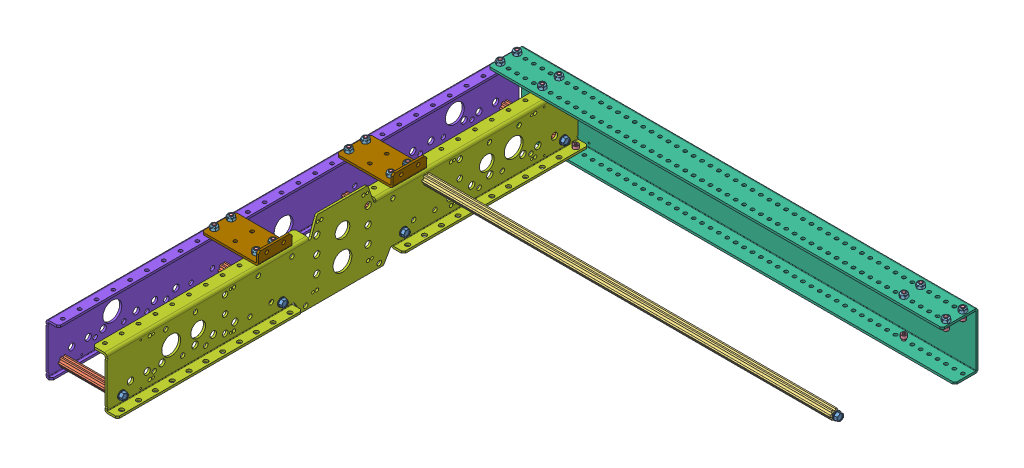
SolidWorks assembly AM14U3 Square Frame Half, configuration Default. Lengths in mm.
Overall size (722.38 428.62 726.08).
57 component instances, 10 part files, 124 mates.
Components (placement in the parent):
- 0.25-20 x 0.75 in Thread Rolling Screw-1: 0.25-20 x 0.75 in Thread Rolling Screw [FHTS 0.25-20-G-0.75-C] at (-600.075 -67.691 639.064) x (-1 0 0) z (0 0.924225 0.381849) size (24.64 12.19 12.19)
- 0.25-20 x 0.75 in Thread Rolling Screw-4: 0.25-20 x 0.75 in Thread Rolling Screw [FHTS 0.25-20-G-0.75-C] at (-600.075 -67.691 -27.94) x (-1 0 0) z (0 0.924225 0.381849) size (24.64 12.19 12.19)
- 0.25-20 x 0.75 in Thread Rolling Screw-5: 0.25-20 x 0.75 in Thread Rolling Screw [FHTS 0.25-20-G-0.75-C] at (-692.15 -67.691 -27.813) size (24.64 12.19 12.19)
- 0.25-20 x 0.75 in Thread Rolling Screw-7: 0.25-20 x 0.75 in Thread Rolling Screw [FHTS 0.25-20-G-0.75-C] at (-603.25 -15.494 178.562) size (24.64 12.19 12.19)
- 0.25-20 x 0.75 in Thread Rolling Screw-9: 0.25-20 x 0.75 in Thread Rolling Screw [FHTS 0.25-20-G-0.75-C] at (-692.15 -67.691 638.937) size (24.64 12.19 12.19)
- 0.25-20 x 0.75 in Thread Rolling Screw-10: 0.25-20 x 0.75 in Thread Rolling Screw [FHTS 0.25-20-G-0.75-C] at (19.05 -15.494 178.562) x (-1 0 0) z (0 0.525103 -0.851039) size (24.64 12.19 12.19)
- 500 Churro 3.375 in-1: 500 Churro 3.375 in [Default] at (-603.25 -67.691 -27.813) x (0 -0.866025 0.5) z (-1 0 0) size (14.66 12.7 85.72)
- 500 Churro 3.375 in-2: 500 Churro 3.375 in [Default] at (-603.25 -67.691 638.937) x (0 -0.866025 0.5) z (-1 0 0) size (14.66 12.7 85.72)
- 500 Churro 24.25 in-1: 500 Churro 24.25 in [Default] at (15.875 -15.494 178.562) x (0 0 -1) z (-1 0 0) size (14.66 12.7 615.95)
- 10-32 x 0.5 in SHCS Screw-19: 10-32 x 0.5 in SHCS Screw [HX-SHCS 0.19-32x1.375x1-C] at (-679.45 -11.43 -11.938) x (0 1 0) z (0 0 1) size (17.53 7.94 7.94)
- 10-32 x 0.5 in SHCS Screw-20: 10-32 x 0.5 in SHCS Screw [HX-SHCS 0.19-32x1.375x1-C] at (-679.45 -11.43 -37.338) x (0 1 0) z (0 0 1) size (17.53 7.94 7.94)
- 10-32 x 0.5 in SHCS Screw-21: 10-32 x 0.5 in SHCS Screw [HX-SHCS 0.19-32x1.375x1-C] at (-615.95 -11.43 -37.338) x (0 1 0) z (0 0 1) size (17.53 7.94 7.94)
- 10-32 x 0.5 in SHCS Screw-22: 10-32 x 0.5 in SHCS Screw [HX-SHCS 0.19-32x1.375x1-C] at (-615.95 -11.43 -11.938) x (0 1 0) z (0 0 1) size (17.53 7.94 7.94)
- 10-32 x 0.5 in SHCS Screw-23: 10-32 x 0.5 in SHCS Screw [HX-SHCS 0.19-32x1.375x1-C] at (-590.55 -73.152 -37.338) x (0 -1 0) z (0 0 1) size (17.53 7.94 7.94)
- 10-32 x 0.5 in SHCS Screw-24: 10-32 x 0.5 in SHCS Screw [HX-SHCS 0.19-32x1.375x1-C] at (-6.35 -11.176 -37.338) x (0 1 0) z (0.222581 0 0.974914) size (17.53 7.94 7.94)
- 10-32 x 0.5 in SHCS Screw-25: 10-32 x 0.5 in SHCS Screw [HX-SHCS 0.19-32x1.375x1-C] at (-6.35 -11.176 -11.938) x (0 1 0) z (0.81526 0 0.579096) size (17.53 7.94 7.94)
- 10-32 x 0.5 in SHCS Screw-26: 10-32 x 0.5 in SHCS Screw [HX-SHCS 0.19-32x1.375x1-C] at (-69.85 -11.176 -37.338) x (0 1 0) z (0 0 1) size (17.53 7.94 7.94)
- 10-32 x 0.5 in SHCS Screw-27: 10-32 x 0.5 in SHCS Screw [HX-SHCS 0.19-32x1.375x1-C] at (-69.85 -11.176 -11.938) x (0 1 0) z (0.111454 0 0.99377) size (17.53 7.94 7.94)
- 10-32 x 0.5 in SHCS Screw-28: 10-32 x 0.5 in SHCS Screw [HX-SHCS 0.19-32x1.375x1-C] at (-95.25 -73.406 -37.338) x (0 -1 0) z (0.007214 0 0.999974) size (17.53 7.94 7.94)
- 10-32 Nylock Nut-19: 10-32 Nylock Nut [Default] at (-679.45 0 -11.938) x (1 0 0) z (0 1 0) size (10.18 11.01 7.1)
- 10-32 Nylock Nut-21: 10-32 Nylock Nut [Default] at (-679.45 0 -37.338) x (1 0 0) z (0 1 0) size (10.18 11.01 7.1)
- 10-32 Nylock Nut-22: 10-32 Nylock Nut [Default] at (-615.95 0 -11.938) x (1 0 0) z (0 1 0) size (10.18 11.01 7.1)
- 10-32 Nylock Nut-23: 10-32 Nylock Nut [Default] at (-615.95 0 -37.338) x (1 0 0) z (0 1 0) size (10.18 11.01 7.1)
- 10-32 Nylock Nut-25: 10-32 Nylock Nut [Default] at (-69.85 0 -11.938) x (1 0 0) z (0 1 0) size (10.18 11.01 7.1)
- 10-32 Nylock Nut-26: 10-32 Nylock Nut [Default] at (-69.85 0 -37.338) x (1 0 0) z (0 1 0) size (10.18 11.01 7.1)
- 10-32 Nylock Nut-27: 10-32 Nylock Nut [Default] at (-6.35 0 -11.938) x (1 0 0) z (0 1 0) size (10.18 11.01 7.1)
- 10-32 Nylock Nut-28: 10-32 Nylock Nut [Default] at (-6.35 0 -37.338) x (1 0 0) z (0 1 0) size (10.18 11.01 7.1)
- 10-32 Nylock Nut-29: 10-32 Nylock Nut [Default] at (-95.25 -84.582 -37.338) x (1 0 0) z (0 -1 0) size (10.18 11.01 7.1)
- 10-32 Nylock Nut-30: 10-32 Nylock Nut [Default] at (-590.55 -84.582 -37.338) x (1 0 0) z (0 -1 0) size (10.18 11.01 7.1)
- 10-32 x 0.5 in SHCS Screw-29: 10-32 x 0.5 in SHCS Screw [HX-SHCS 0.19-32x1.375x1-C] at (-679.45 -11.43 191.262) x (0 1 0) z (0 0 1) size (17.53 7.94 7.94)
- 10-32 x 0.5 in SHCS Screw-30: 10-32 x 0.5 in SHCS Screw [HX-SHCS 0.19-32x1.375x1-C] at (-679.45 -11.43 216.662) x (0 1 0) z (0 0 1) size (17.53 7.94 7.94)
- 10-32 x 0.5 in SHCS Screw-31: 10-32 x 0.5 in SHCS Screw [HX-SHCS 0.19-32x1.375x1-C] at (-615.95 -11.43 191.262) x (0 1 0) z (0 0 1) size (17.53 7.94 7.94)
- 10-32 x 0.5 in SHCS Screw-32: 10-32 x 0.5 in SHCS Screw [HX-SHCS 0.19-32x1.375x1-C] at (-615.95 -11.43 216.662) x (0 1 0) z (0 0 1) size (17.53 7.94 7.94)
- 10-32 x 0.5 in SHCS Screw-33: 10-32 x 0.5 in SHCS Screw [HX-SHCS 0.19-32x1.375x1-C] at (-615.95 -11.43 394.462) x (0 1 0) z (0 0 1) size (17.53 7.94 7.94)
- 10-32 x 0.5 in SHCS Screw-34: 10-32 x 0.5 in SHCS Screw [HX-SHCS 0.19-32x1.375x1-C] at (-615.95 -11.43 419.862) x (0 1 0) z (0 0 1) size (17.53 7.94 7.94)
- 10-32 x 0.5 in SHCS Screw-35: 10-32 x 0.5 in SHCS Screw [HX-SHCS 0.19-32x1.375x1-C] at (-679.45 -11.43 394.462) x (0 1 0) z (0 0 1) size (17.53 7.94 7.94)
- 10-32 x 0.5 in SHCS Screw-36: 10-32 x 0.5 in SHCS Screw [HX-SHCS 0.19-32x1.375x1-C] at (-679.45 -11.43 419.862) x (0 1 0) z (0 0 1) size (17.53 7.94 7.94)
- 10-32 Nylock Nut-31: 10-32 Nylock Nut [Default] at (-679.45 -0.254 419.862) x (1 0 0) z (0 1 0) size (10.18 11.01 7.1)
- 10-32 Nylock Nut-32: 10-32 Nylock Nut [Default] at (-679.45 -0.254 394.462) x (1 0 0) z (0 1 0) size (10.18 11.01 7.1)
- 10-32 Nylock Nut-33: 10-32 Nylock Nut [Default] at (-615.95 -0.254 394.462) x (1 0 0) z (0 1 0) size (10.18 11.01 7.1)
- 10-32 Nylock Nut-34: 10-32 Nylock Nut [Default] at (-615.95 -0.254 419.862) x (1 0 0) z (0 1 0) size (10.18 11.01 7.1)
- 10-32 Nylock Nut-35: 10-32 Nylock Nut [Default] at (-679.45 -0.254 216.662) x (1 0 0) z (0 1 0) size (10.18 11.01 7.1)
- 10-32 Nylock Nut-37: 10-32 Nylock Nut [Default] at (-679.45 -0.254 191.262) x (1 0 0) z (0 1 0) size (10.18 11.01 7.1)
- 10-32 Nylock Nut-38: 10-32 Nylock Nut [Default] at (-615.95 -0.254 216.662) x (1 0 0) z (0 1 0) size (10.18 11.01 7.1)
- 10-32 Nylock Nut-39: 10-32 Nylock Nut [Default] at (-615.95 -0.254 191.262) x (1 0 0) z (0 1 0) size (10.18 11.01 7.1)
- AM14U3 End Plate_Square-1: AM14U3 End Plate_Square [Default] at (-488.098 60.9785 -76.8664) x (1 0 0) z (0 -1 0) size (685.8 53.97 84.58)
- AM14U3 Inner Plate_Square-1: AM14U3 Inner Plate_Square [Default] at (-612.1116 -19.2169 590.6409) x (0 0 -1) z (0 -1 0) size (711.2 38.1 116.33)
- AM14U3 Outer Plate_Square-1: AM14U3 Outer Plate_Square [Default] at (-667.7485 -27.0221 21.6115) x (0 0 1) z (0 -1 0) size (711.2 19.05 77.72)
- Bracket 2x3 Hole Pattern-1: Bracket 2x3 Hole Pattern [Default] at (-685.8 -3.429 445.262) size (85.72 19.05 50.8)
- Bracket 2x3 Hole Pattern-2: Bracket 2x3 Hole Pattern [Default] at (-685.8 -3.429 242.062) size (85.72 19.05 50.8)
- 500 Churro 3.375 in-5: 500 Churro 3.375 in [Default] at (-688.975 -66.929 397.637) x (0 0 -1) z (1 0 0) size (14.66 12.7 85.72)
- 500 Churro 3.375 in-6: 500 Churro 3.375 in [Default] at (-688.975 -66.929 213.487) x (0 0 -1) z (1 0 0) size (14.66 12.7 85.72)
- 0.25-20 x 0.75 in Thread Rolling Screw-11: 0.25-20 x 0.75 in Thread Rolling Screw [FHTS 0.25-20-G-0.75-C] at (-600.075 -66.929 397.637) x (-1 0 0) z (0 0.924225 0.381849) size (24.64 12.19 12.19)
- 0.25-20 x 0.75 in Thread Rolling Screw-12: 0.25-20 x 0.75 in Thread Rolling Screw [FHTS 0.25-20-G-0.75-C] at (-600.075 -66.929 213.487) x (-1 0 0) z (0 0.924225 0.381849) size (24.64 12.19 12.19)
- 0.25-20 x 0.75 in Thread Rolling Screw-13: 0.25-20 x 0.75 in Thread Rolling Screw [FHTS 0.25-20-G-0.75-C] at (-692.15 -66.929 397.637) size (24.64 12.19 12.19)
- 0.25-20 x 0.75 in Thread Rolling Screw-14: 0.25-20 x 0.75 in Thread Rolling Screw [FHTS 0.25-20-G-0.75-C] at (-692.15 -66.929 213.487) size (24.64 12.19 12.19)
- side-view-with-wheels-1: side-view-with-wheels [Default] x (0 0 -1) z (1 0 0) size (718.98 241.48 0)
Mates (geometry in assembly coordinates):
- Coincident1: coincident aligned: plane of AM14U3 End Plate_Square-1 through (0 0 0) normal (0 1 0); plane of assembly through (0 0 0) normal (0 1 0)
- Coincident2: coincident aligned: plane of AM14U3 End Plate_Square-1 through (0 0 0) normal (0 0 1); plane of assembly through (0 0 0) normal (0 0 1)
- Coincident3: coincident aligned: plane of AM14U3 End Plate_Square-1 through (0 -81.407 -50.8) normal (1 0 0); plane of assembly through (0 0 0) normal (1 0 0)
- Concentric1: concentric anti-aligned: cylinder of AM14U3 End Plate_Square-1 through (-679.45 0 -37.338) axis (0 -1 0) radius 2.667; cylinder of AM14U3 Outer Plate_Square-1 through (-679.45 -81.153 -37.338) axis (0 1 0) radius 2.667
- Concentric2: concentric aligned: cylinder of AM14U3 End Plate_Square-1 through (-679.45 -5.08 -11.938) axis (0 1 0) radius 2.667; cylinder of AM14U3 Outer Plate_Square-1 through (-679.45 -81.153 -11.938) axis (0 1 0) radius 2.667
- Concentric3: concentric anti-aligned: cylinder of AM14U3 End Plate_Square-1 through (-615.95 0 -37.338) axis (0 -1 0) radius 2.667; cylinder of AM14U3 Inner Plate_Square-1 through (-615.95 -81.153 -37.338) axis (0 1 0) radius 2.667
- Coincident5: coincident aligned: circle of AM14U3 End Plate_Square-1; cylinder of AM14U3 Inner Plate_Square-1 through (-615.95 -81.153 -11.938) axis (0 1 0) radius 2.667
- Distance2: distance = 0.254 mm anti-aligned: plane of AM14U3 Inner Plate_Square-1 through (-603.25 -3.429 -100.838) normal (0 1 0); plane of AM14U3 End Plate_Square-1 through (0 -3.175 0) normal (0 -1 0)
- Concentric4: concentric aligned: cylinder of AM14U3 Inner Plate_Square-1 through (-615.95 -81.153 394.462) axis (0 1 0) radius 2.667; cylinder of Bracket 2x3 Hole Pattern-1 through (-615.95 -3.429 394.462) axis (0 1 0) radius 2.667
- Coincident7: coincident aligned: cylinder of AM14U3 Inner Plate_Square-1 through (-615.95 -81.153 419.862) axis (0 1 0) radius 2.667; circle of Bracket 2x3 Hole Pattern-1
- Coincident8: coincident anti-aligned: plane of AM14U3 Inner Plate_Square-1 through (-603.25 -3.429 -100.838) normal (0 1 0); plane of Bracket 2x3 Hole Pattern-1 through (-685.8 -3.429 381.762) normal (0 -1 0)
- Concentric5: concentric aligned: cylinder of AM14U3 Inner Plate_Square-1 through (-615.95 -81.153 216.662) axis (0 1 0) radius 2.667; cylinder of Bracket 2x3 Hole Pattern-2 through (-615.95 -3.429 216.662) axis (0 1 0) radius 2.667
- Concentric6: concentric aligned: cylinder of AM14U3 Inner Plate_Square-1 through (-615.95 -81.153 191.262) axis (0 1 0) radius 2.667; cylinder of Bracket 2x3 Hole Pattern-2 through (-615.95 -3.429 191.262) axis (0 1 0) radius 2.667
- Coincident9: coincident anti-aligned: plane of AM14U3 Inner Plate_Square-1 through (-603.25 -3.429 -100.838) normal (0 1 0); plane of Bracket 2x3 Hole Pattern-2 through (-685.8 -3.429 178.562) normal (0 -1 0)
- Concentric25: concentric anti-aligned: cylinder of AM14U3 Outer Plate_Square-1 through (-673.1 -67.691 -27.813) axis (-1 0 0) radius 3.3528; cylinder of 500 Churro 3.375 in-1 through (-688.975 -67.691 -27.813) axis (1 0 0) radius 2.9337
- Concentric26: concentric anti-aligned: cylinder of AM14U3 Outer Plate_Square-1 through (-673.1 -67.691 638.937) axis (-1 0 0) radius 3.3528; cylinder of 500 Churro 3.375 in-2 through (-688.975 -67.691 638.937) axis (1 0 0) radius 2.9337
- Coincident28: coincident anti-aligned: plane of AM14U3 Outer Plate_Square-1 through (-688.975 -7.366 -100.838) normal (1 0 0); plane of 500 Churro 3.375 in-2 through (-688.975 -70.866 644.4363) normal (-1 0 0)
- Parallel1: parallel aligned: plane of AM14U3 Outer Plate_Square-1 through (-688.975 -81.153 711.962) normal (0 -1 0); plane of 500 Churro 3.375 in-2 through (-688.975 -74.041 635.2708) normal (0 -1 0)
- Coincident30: coincident anti-aligned: plane of AM14U3 Outer Plate_Square-1 through (-688.975 -7.366 -100.838) normal (1 0 0); plane of 500 Churro 3.375 in-1 through (-688.975 -70.866 -22.3137) normal (-1 0 0)
- Parallel2: parallel aligned: plane of AM14U3 Outer Plate_Square-1 through (-688.975 -81.153 711.962) normal (0 -1 0); plane of 500 Churro 3.375 in-1 through (-688.975 -74.041 -31.4792) normal (0 -1 0)
- Distance3: distance = 0.254 mm anti-aligned: plane of AM14U3 Outer Plate_Square-1 through (-688.975 -3.429 711.962) normal (0 1 0); plane of AM14U3 End Plate_Square-1 through (0 -3.175 0) normal (0 -1 0)
- Concentric29: concentric anti-aligned: circle of AM14U3 Inner Plate_Square-1; cylinder of 500 Churro 24.25 in-1 through (-600.075 -15.494 178.562) axis (1 0 0) radius 2.9337
- Coincident37: coincident anti-aligned: plane of AM14U3 Inner Plate_Square-1 through (-600.075 -7.366 711.962) normal (1 0 0); plane of 500 Churro 24.25 in-1 through (-600.075 -18.669 173.0627) normal (-1 0 0)
- Concentric301: concentric aligned: cylinder of AM14U3 Inner Plate_Square-1 through (-622.3 -67.691 639.064) axis (1 0 0) radius 3.3528; cylinder of 0.25-20 x 0.75 in Thread Rolling Screw-1 through (-600.075 -67.691 639.064) axis (1 0 0) radius 3.175
- Coincident381: coincident anti-aligned: plane of AM14U3 Inner Plate_Square-1 through (-600.075 -7.366 711.962) normal (1 0 0); plane of 0.25-20 x 0.75 in Thread Rolling Screw-1 through (-600.075 -68.9034 641.9984) normal (-1 0 0)
- Concentric331: concentric aligned: cylinder of AM14U3 Inner Plate_Square-1 through (-622.3 -67.691 -27.94) axis (1 0 0) radius 3.3528; cylinder of 0.25-20 x 0.75 in Thread Rolling Screw-4 through (-600.075 -67.691 -27.94) axis (1 0 0) radius 3.175
- Coincident411: coincident anti-aligned: plane of AM14U3 Inner Plate_Square-1 through (-600.075 -7.366 711.962) normal (1 0 0); plane of 0.25-20 x 0.75 in Thread Rolling Screw-4 through (-600.075 -68.9034 -25.0056) normal (-1 0 0)
- Concentric341: concentric aligned: cylinder of AM14U3 Outer Plate_Square-1 through (-673.1 -67.691 -27.813) axis (-1 0 0) radius 3.3528; cylinder of 0.25-20 x 0.75 in Thread Rolling Screw-5 through (-692.15 -67.691 -27.813) axis (-1 0 0) radius 3.175
- Coincident421: coincident anti-aligned: plane of AM14U3 Outer Plate_Square-1 through (-692.15 -7.366 -100.838) normal (-1 0 0); plane of 0.25-20 x 0.75 in Thread Rolling Screw-5 through (-692.15 -64.516 -27.813) normal (1 0 0)
- Concentric361: concentric aligned: cylinder of AM14U3 Inner Plate_Square-1 through (-584.2 -15.494 178.562) axis (-1 0 0) radius 3.3528; cylinder of 0.25-20 x 0.75 in Thread Rolling Screw-7 through (-603.25 -15.494 178.562) axis (-1 0 0) radius 3.175
- Coincident441: coincident anti-aligned: plane of AM14U3 Inner Plate_Square-1 through (-603.25 -7.366 711.962) normal (-1 0 0); plane of 0.25-20 x 0.75 in Thread Rolling Screw-7 through (-603.25 -12.319 178.562) normal (1 0 0)
- Concentric381: concentric aligned: cylinder of AM14U3 Outer Plate_Square-1 through (-673.1 -67.691 638.937) axis (-1 0 0) radius 3.3528; cylinder of 0.25-20 x 0.75 in Thread Rolling Screw-9 through (-692.15 -67.691 638.937) axis (-1 0 0) radius 3.175
- Coincident461: coincident anti-aligned: plane of AM14U3 Outer Plate_Square-1 through (-692.15 -7.366 -100.838) normal (-1 0 0); plane of 0.25-20 x 0.75 in Thread Rolling Screw-9 through (-692.15 -64.516 638.937) normal (1 0 0)
- Concentric39: concentric aligned: cylinder of 500 Churro 24.25 in-1 through (-600.075 -15.494 178.562) axis (1 0 0) radius 2.9337; cylinder of 0.25-20 x 0.75 in Thread Rolling Screw-10 through (19.05 -15.494 178.562) axis (1 0 0) radius 3.175
- Distance4: distance = 3.175 mm anti-aligned: plane of 500 Churro 24.25 in-1 through (15.875 -18.669 173.0627) normal (1 0 0); plane of 0.25-20 x 0.75 in Thread Rolling Screw-10 through (19.05 -12.792 180.2292) normal (-1 0 0)
- Parallel5: parallel aligned: plane of AM14U3 Inner Plate_Square-1 through (-603.25 -3.429 -100.838) normal (0 1 0); plane of 500 Churro 24.25 in-1 through (-600.075 -9.144 176.9745) normal (0 1 0)
- Concentric4721: concentric anti-aligned: cylinder of AM14U3 Outer Plate_Square-1 through (-679.45 -81.153 -11.938) axis (0 1 0) radius 2.667; cylinder of 10-32 x 0.5 in SHCS Screw-19 through (-679.45 -43.18 -11.938) axis (0 -1 0) radius 3.9688
- Coincident5621: coincident anti-aligned: plane of AM14U3 Outer Plate_Square-1 through (-688.975 -6.604 711.962) normal (0 -1 0); plane of 10-32 x 0.5 in SHCS Screw-19 through (-683.4187 -6.604 -11.938) normal (0 1 0)
- Concentric4731: concentric anti-aligned: cylinder of AM14U3 Outer Plate_Square-1 through (-679.45 -81.153 -37.338) axis (0 1 0) radius 2.667; cylinder of 10-32 x 0.5 in SHCS Screw-20 through (-679.45 -43.18 -37.338) axis (0 -1 0) radius 3.9688
- Coincident5631: coincident anti-aligned: plane of AM14U3 Outer Plate_Square-1 through (-688.975 -6.604 711.962) normal (0 -1 0); plane of 10-32 x 0.5 in SHCS Screw-20 through (-683.4187 -6.604 -37.338) normal (0 1 0)
- Concentric4741: concentric anti-aligned: cylinder of AM14U3 Inner Plate_Square-1 through (-615.95 -81.153 -37.338) axis (0 1 0) radius 2.667; cylinder of 10-32 x 0.5 in SHCS Screw-21 through (-615.95 -43.18 -37.338) axis (0 -1 0) radius 3.9688
- Coincident5641: coincident anti-aligned: plane of AM14U3 Inner Plate_Square-1 through (-603.25 -6.604 -100.838) normal (0 -1 0); plane of 10-32 x 0.5 in SHCS Screw-21 through (-619.9187 -6.604 -37.338) normal (0 1 0)
- Concentric4751: concentric anti-aligned: cylinder of AM14U3 Inner Plate_Square-1 through (-615.95 -81.153 -11.938) axis (0 1 0) radius 2.667; cylinder of 10-32 x 0.5 in SHCS Screw-22 through (-615.95 -43.18 -11.938) axis (0 -1 0) radius 3.9688
- Coincident5651: coincident anti-aligned: plane of AM14U3 Inner Plate_Square-1 through (-603.25 -6.604 -100.838) normal (0 -1 0); plane of 10-32 x 0.5 in SHCS Screw-22 through (-619.9187 -6.604 -11.938) normal (0 1 0)
- Concentric4761: concentric aligned: cylinder of AM14U3 Inner Plate_Square-1 through (-590.55 -81.153 -37.338) axis (0 1 0) radius 3.3528; cylinder of 10-32 x 0.5 in SHCS Screw-23 through (-590.55 -41.402 -37.338) axis (0 1 0) radius 3.9688
- Coincident5661: coincident anti-aligned: plane of AM14U3 Inner Plate_Square-1 through (-600.075 -77.978 -100.838) normal (0 1 0); plane of 10-32 x 0.5 in SHCS Screw-23 through (-586.5813 -77.978 -37.338) normal (0 -1 0)
- Concentric478: concentric aligned: cylinder of AM14U3 End Plate_Square-1 through (-6.35 0 -37.338) axis (0 -1 0) radius 2.667; cylinder of 10-32 x 0.5 in SHCS Screw-24 through (-6.35 -42.926 -37.338) axis (0 -1 0) radius 2.413
- Concentric479: concentric anti-aligned: cylinder of AM14U3 End Plate_Square-1 through (-6.35 -5.08 -11.938) axis (0 1 0) radius 2.667; cylinder of 10-32 x 0.5 in SHCS Screw-25 through (-6.35 -42.926 -11.938) axis (0 -1 0) radius 2.413
- Coincident567: coincident aligned: plane of 10-32 x 0.5 in SHCS Screw-24 through (-10.2192 -6.35 -36.4546) normal (0 1 0); plane of 10-32 x 0.5 in SHCS Screw-25 through (-8.6483 -6.35 -8.7024) normal (0 1 0)
- Concentric480: concentric aligned: cylinder of AM14U3 End Plate_Square-1 through (-69.85 0 -37.338) axis (0 -1 0) radius 2.667; cylinder of 10-32 x 0.5 in SHCS Screw-26 through (-69.85 -42.926 -37.338) axis (0 -1 0) radius 2.413
- Concentric481: concentric anti-aligned: cylinder of AM14U3 End Plate_Square-1 through (-69.85 -5.08 -11.938) axis (0 1 0) radius 2.667; cylinder of 10-32 x 0.5 in SHCS Screw-27 through (-69.85 -42.926 -11.938) axis (0 -1 0) radius 2.413
- Coincident568: coincident aligned: plane of 10-32 x 0.5 in SHCS Screw-26 through (-73.8188 -6.35 -37.338) normal (0 1 0); plane of 10-32 x 0.5 in SHCS Screw-27 through (-73.794 -6.35 -11.4957) normal (0 1 0)
- Coincident569: coincident aligned: plane of 10-32 x 0.5 in SHCS Screw-25 through (-8.6483 -6.35 -8.7024) normal (0 1 0); plane of 10-32 x 0.5 in SHCS Screw-27 through (-73.794 -6.35 -11.4957) normal (0 1 0)
- Distance5: distance = 3.175 mm anti-aligned: plane of AM14U3 End Plate_Square-1 through (0 -3.175 0) normal (0 -1 0); plane of 10-32 x 0.5 in SHCS Screw-27 through (-73.794 -6.35 -11.4957) normal (0 1 0)
- Concentric482: concentric aligned: circle of AM14U3 End Plate_Square-1; cylinder of 10-32 x 0.5 in SHCS Screw-28 through (-95.25 -41.656 -37.338) axis (0 1 0) radius 2.413
- Distance6: distance = 3.175 mm anti-aligned: plane of AM14U3 End Plate_Square-1 through (-787.4 -81.407 -19.05) normal (0 1 0); plane of 10-32 x 0.5 in SHCS Screw-28 through (-91.2814 -78.232 -37.3666) normal (0 -1 0)
- Concentric4831: concentric aligned: cylinder of AM14U3 End Plate_Square-1 through (-679.45 -5.08 -11.938) axis (0 1 0) radius 2.667; cylinder of 10-32 Nylock Nut-19 through (-679.45 5.9531 -11.938) axis (0 1 0) radius 2.0193
- Coincident5721: coincident anti-aligned: plane of AM14U3 End Plate_Square-1 through (0 0 0) normal (0 1 0); plane of 10-32 Nylock Nut-19 through (-679.45 0 -11.938) normal (0 -1 0)
- Concentric4841: concentric anti-aligned: cylinder of AM14U3 End Plate_Square-1 through (-679.45 0 -37.338) axis (0 -1 0) radius 2.667; cylinder of 10-32 Nylock Nut-21 through (-679.45 5.9531 -37.338) axis (0 1 0) radius 2.0193
- Coincident5731: coincident anti-aligned: plane of AM14U3 End Plate_Square-1 through (0 0 0) normal (0 1 0); plane of 10-32 Nylock Nut-21 through (-679.45 0 -37.338) normal (0 -1 0)
- Concentric4851: concentric aligned: cylinder of AM14U3 End Plate_Square-1 through (-615.95 -5.08 -11.938) axis (0 1 0) radius 2.667; cylinder of 10-32 Nylock Nut-22 through (-615.95 5.9531 -11.938) axis (0 1 0) radius 2.0193
- Coincident5741: coincident anti-aligned: plane of AM14U3 End Plate_Square-1 through (0 0 0) normal (0 1 0); plane of 10-32 Nylock Nut-22 through (-615.95 0 -11.938) normal (0 -1 0)
- Concentric4861: concentric anti-aligned: cylinder of AM14U3 End Plate_Square-1 through (-615.95 0 -37.338) axis (0 -1 0) radius 2.667; cylinder of 10-32 Nylock Nut-23 through (-615.95 5.9531 -37.338) axis (0 1 0) radius 2.0193
- Coincident5751: coincident anti-aligned: plane of AM14U3 End Plate_Square-1 through (0 0 0) normal (0 1 0); plane of 10-32 Nylock Nut-23 through (-615.95 0 -37.338) normal (0 -1 0)
- Concentric4871: concentric aligned: cylinder of AM14U3 End Plate_Square-1 through (-69.85 -5.08 -11.938) axis (0 1 0) radius 2.667; cylinder of 10-32 Nylock Nut-25 through (-69.85 5.9531 -11.938) axis (0 1 0) radius 2.0193
- Coincident5771: coincident anti-aligned: plane of AM14U3 End Plate_Square-1 through (0 0 0) normal (0 1 0); plane of 10-32 Nylock Nut-25 through (-69.85 0 -11.938) normal (0 -1 0)
- Concentric4881: concentric anti-aligned: cylinder of AM14U3 End Plate_Square-1 through (-69.85 0 -37.338) axis (0 -1 0) radius 2.667; cylinder of 10-32 Nylock Nut-26 through (-69.85 5.9531 -37.338) axis (0 1 0) radius 2.0193
- Coincident5781: coincident anti-aligned: plane of AM14U3 End Plate_Square-1 through (0 0 0) normal (0 1 0); plane of 10-32 Nylock Nut-26 through (-69.85 0 -37.338) normal (0 -1 0)
- Concentric4891: concentric aligned: cylinder of AM14U3 End Plate_Square-1 through (-6.35 -5.08 -11.938) axis (0 1 0) radius 2.667; cylinder of 10-32 Nylock Nut-27 through (-6.35 5.9531 -11.938) axis (0 1 0) radius 2.0193
- Coincident5791: coincident anti-aligned: plane of AM14U3 End Plate_Square-1 through (0 0 0) normal (0 1 0); plane of 10-32 Nylock Nut-27 through (-6.35 0 -11.938) normal (0 -1 0)
- Concentric4901: concentric anti-aligned: cylinder of AM14U3 End Plate_Square-1 through (-6.35 0 -37.338) axis (0 -1 0) radius 2.667; cylinder of 10-32 Nylock Nut-28 through (-6.35 5.9531 -37.338) axis (0 1 0) radius 2.0193
- Coincident5801: coincident anti-aligned: plane of AM14U3 End Plate_Square-1 through (0 0 0) normal (0 1 0); plane of 10-32 Nylock Nut-28 through (-6.35 0 -37.338) normal (0 -1 0)
- Concentric4911: concentric aligned: cylinder of AM14U3 End Plate_Square-1 through (-95.25 0 -37.338) axis (0 -1 0) radius 2.667; cylinder of 10-32 Nylock Nut-29 through (-95.25 -90.5351 -37.338) axis (0 -1 0) radius 2.0193
- Coincident5811: coincident anti-aligned: plane of AM14U3 End Plate_Square-1 through (-787.4 -84.582 -19.05) normal (0 -1 0); plane of 10-32 Nylock Nut-29 through (-95.25 -84.582 -37.338) normal (0 1 0)
- Concentric4921: concentric aligned: cylinder of AM14U3 End Plate_Square-1 through (-590.55 0 -37.338) axis (0 -1 0) radius 2.667; cylinder of 10-32 Nylock Nut-30 through (-590.55 -90.5351 -37.338) axis (0 -1 0) radius 2.0193
- Coincident5821: coincident anti-aligned: plane of AM14U3 End Plate_Square-1 through (-787.4 -84.582 -19.05) normal (0 -1 0); plane of 10-32 Nylock Nut-30 through (-590.55 -84.582 -37.338) normal (0 1 0)
- Concentric4931: concentric anti-aligned: cylinder of AM14U3 Outer Plate_Square-1 through (-679.45 -81.153 191.262) axis (0 1 0) radius 2.667; cylinder of 10-32 x 0.5 in SHCS Screw-29 through (-679.45 -43.18 191.262) axis (0 -1 0) radius 3.9688
- Coincident5831: coincident anti-aligned: plane of AM14U3 Outer Plate_Square-1 through (-688.975 -6.604 711.962) normal (0 -1 0); plane of 10-32 x 0.5 in SHCS Screw-29 through (-683.4187 -6.604 191.262) normal (0 1 0)
- Concentric4941: concentric anti-aligned: cylinder of AM14U3 Outer Plate_Square-1 through (-679.45 -81.153 216.662) axis (0 1 0) radius 2.667; cylinder of 10-32 x 0.5 in SHCS Screw-30 through (-679.45 -43.18 216.662) axis (0 -1 0) radius 3.9688
- Coincident5841: coincident anti-aligned: plane of AM14U3 Outer Plate_Square-1 through (-688.975 -6.604 711.962) normal (0 -1 0); plane of 10-32 x 0.5 in SHCS Screw-30 through (-683.4187 -6.604 216.662) normal (0 1 0)
- Concentric4951: concentric anti-aligned: cylinder of AM14U3 Inner Plate_Square-1 through (-615.95 -81.153 191.262) axis (0 1 0) radius 2.667; cylinder of 10-32 x 0.5 in SHCS Screw-31 through (-615.95 -43.18 191.262) axis (0 -1 0) radius 3.9688
- Coincident5851: coincident anti-aligned: plane of AM14U3 Inner Plate_Square-1 through (-603.25 -6.604 -100.838) normal (0 -1 0); plane of 10-32 x 0.5 in SHCS Screw-31 through (-619.9187 -6.604 191.262) normal (0 1 0)
- Concentric4961: concentric anti-aligned: cylinder of AM14U3 Inner Plate_Square-1 through (-615.95 -81.153 216.662) axis (0 1 0) radius 2.667; cylinder of 10-32 x 0.5 in SHCS Screw-32 through (-615.95 -43.18 216.662) axis (0 -1 0) radius 3.9688
- Coincident5861: coincident anti-aligned: plane of AM14U3 Inner Plate_Square-1 through (-603.25 -6.604 -100.838) normal (0 -1 0); plane of 10-32 x 0.5 in SHCS Screw-32 through (-619.9187 -6.604 216.662) normal (0 1 0)
- Concentric4971: concentric anti-aligned: cylinder of AM14U3 Inner Plate_Square-1 through (-615.95 -81.153 394.462) axis (0 1 0) radius 2.667; cylinder of 10-32 x 0.5 in SHCS Screw-33 through (-615.95 -43.18 394.462) axis (0 -1 0) radius 3.9688
- Coincident5871: coincident anti-aligned: plane of AM14U3 Inner Plate_Square-1 through (-603.25 -6.604 -100.838) normal (0 -1 0); plane of 10-32 x 0.5 in SHCS Screw-33 through (-619.9187 -6.604 394.462) normal (0 1 0)
- Concentric4981: concentric anti-aligned: cylinder of AM14U3 Inner Plate_Square-1 through (-615.95 -81.153 419.862) axis (0 1 0) radius 2.667; cylinder of 10-32 x 0.5 in SHCS Screw-34 through (-615.95 -43.18 419.862) axis (0 -1 0) radius 3.9688
- Coincident5881: coincident anti-aligned: plane of AM14U3 Inner Plate_Square-1 through (-603.25 -6.604 -100.838) normal (0 -1 0); plane of 10-32 x 0.5 in SHCS Screw-34 through (-619.9187 -6.604 419.862) normal (0 1 0)
- Concentric4991: concentric anti-aligned: cylinder of AM14U3 Outer Plate_Square-1 through (-679.45 -81.153 394.462) axis (0 1 0) radius 2.667; cylinder of 10-32 x 0.5 in SHCS Screw-35 through (-679.45 -43.18 394.462) axis (0 -1 0) radius 3.9688
- Coincident5891: coincident anti-aligned: plane of AM14U3 Outer Plate_Square-1 through (-688.975 -6.604 711.962) normal (0 -1 0); plane of 10-32 x 0.5 in SHCS Screw-35 through (-683.4187 -6.604 394.462) normal (0 1 0)
- Concentric5001: concentric anti-aligned: cylinder of AM14U3 Outer Plate_Square-1 through (-679.45 -81.153 419.862) axis (0 1 0) radius 2.667; cylinder of 10-32 x 0.5 in SHCS Screw-36 through (-679.45 -43.18 419.862) axis (0 -1 0) radius 3.9688
- Coincident5901: coincident anti-aligned: plane of AM14U3 Outer Plate_Square-1 through (-688.975 -6.604 711.962) normal (0 -1 0); plane of 10-32 x 0.5 in SHCS Screw-36 through (-683.4187 -6.604 419.862) normal (0 1 0)
- Concentric5011: concentric aligned: cylinder of Bracket 2x3 Hole Pattern-1 through (-679.45 -3.429 419.862) axis (0 1 0) radius 2.667; cylinder of 10-32 Nylock Nut-31 through (-679.45 5.6991 419.862) axis (0 1 0) radius 2.0193
- Coincident5911: coincident anti-aligned: plane of Bracket 2x3 Hole Pattern-1 through (-685.8 -0.254 381.762) normal (0 1 0); plane of 10-32 Nylock Nut-31 through (-679.45 -0.254 419.862) normal (0 -1 0)
- Concentric5021: concentric aligned: cylinder of Bracket 2x3 Hole Pattern-1 through (-679.45 -3.429 394.462) axis (0 1 0) radius 2.667; cylinder of 10-32 Nylock Nut-32 through (-679.45 5.6991 394.462) axis (0 1 0) radius 2.0193
- Coincident5921: coincident anti-aligned: plane of Bracket 2x3 Hole Pattern-1 through (-685.8 -0.254 381.762) normal (0 1 0); plane of 10-32 Nylock Nut-32 through (-679.45 -0.254 394.462) normal (0 -1 0)
- Concentric5031: concentric aligned: cylinder of Bracket 2x3 Hole Pattern-1 through (-615.95 -3.429 394.462) axis (0 1 0) radius 2.667; cylinder of 10-32 Nylock Nut-33 through (-615.95 5.6991 394.462) axis (0 1 0) radius 2.0193
- Coincident5931: coincident anti-aligned: plane of Bracket 2x3 Hole Pattern-1 through (-685.8 -0.254 381.762) normal (0 1 0); plane of 10-32 Nylock Nut-33 through (-615.95 -0.254 394.462) normal (0 -1 0)
- Concentric5041: concentric aligned: cylinder of Bracket 2x3 Hole Pattern-1 through (-615.95 -3.429 419.862) axis (0 1 0) radius 2.667; cylinder of 10-32 Nylock Nut-34 through (-615.95 5.6991 419.862) axis (0 1 0) radius 2.0193
- Coincident5941: coincident anti-aligned: plane of Bracket 2x3 Hole Pattern-1 through (-685.8 -0.254 381.762) normal (0 1 0); plane of 10-32 Nylock Nut-34 through (-615.95 -0.254 419.862) normal (0 -1 0)
- Concentric5051: concentric aligned: cylinder of Bracket 2x3 Hole Pattern-2 through (-679.45 -3.429 216.662) axis (0 1 0) radius 2.667; cylinder of 10-32 Nylock Nut-35 through (-679.45 5.6991 216.662) axis (0 1 0) radius 2.0193
- Coincident5951: coincident anti-aligned: plane of Bracket 2x3 Hole Pattern-2 through (-685.8 -0.254 178.562) normal (0 1 0); plane of 10-32 Nylock Nut-35 through (-679.45 -0.254 216.662) normal (0 -1 0)
- Concentric5061: concentric aligned: cylinder of Bracket 2x3 Hole Pattern-2 through (-679.45 -3.429 191.262) axis (0 1 0) radius 2.667; cylinder of 10-32 Nylock Nut-37 through (-679.45 5.6991 191.262) axis (0 1 0) radius 2.0193
- Coincident5961: coincident anti-aligned: plane of Bracket 2x3 Hole Pattern-2 through (-685.8 -0.254 178.562) normal (0 1 0); plane of 10-32 Nylock Nut-37 through (-679.45 -0.254 191.262) normal (0 -1 0)
- Concentric5071: concentric aligned: cylinder of Bracket 2x3 Hole Pattern-2 through (-615.95 -3.429 216.662) axis (0 1 0) radius 2.667; cylinder of 10-32 Nylock Nut-38 through (-615.95 5.6991 216.662) axis (0 1 0) radius 2.0193
- Coincident5971: coincident anti-aligned: plane of Bracket 2x3 Hole Pattern-2 through (-685.8 -0.254 178.562) normal (0 1 0); plane of 10-32 Nylock Nut-38 through (-615.95 -0.254 216.662) normal (0 -1 0)
- Concentric5081: concentric aligned: cylinder of Bracket 2x3 Hole Pattern-2 through (-615.95 -3.429 191.262) axis (0 1 0) radius 2.667; cylinder of 10-32 Nylock Nut-39 through (-615.95 5.6991 191.262) axis (0 1 0) radius 2.0193
- Coincident5981: coincident anti-aligned: plane of Bracket 2x3 Hole Pattern-2 through (-685.8 -0.254 178.562) normal (0 1 0); plane of 10-32 Nylock Nut-39 through (-615.95 -0.254 191.262) normal (0 -1 0)
- Concentric5082: concentric anti-aligned: circle of AM14U3 Inner Plate_Square-1; cylinder of 500 Churro 3.375 in-5 through (-603.25 -66.929 397.637) axis (-1 0 0) radius 2.9337
- Concentric5083: concentric anti-aligned: cylinder of AM14U3 Inner Plate_Square-1 through (-622.3 -66.929 213.487) axis (1 0 0) radius 3.3528; cylinder of 500 Churro 3.375 in-6 through (-603.25 -66.929 213.487) axis (-1 0 0) radius 2.9337
- Coincident5982: coincident aligned: plane of 500 Churro 3.375 in-5 through (-603.25 -63.754 392.1377) normal (1 0 0); plane of 500 Churro 3.375 in-6 through (-603.25 -63.754 207.9877) normal (1 0 0)
- Coincident5983: coincident anti-aligned: plane of AM14U3 Inner Plate_Square-1 through (-603.25 -7.366 711.962) normal (-1 0 0); plane of 500 Churro 3.375 in-5 through (-603.25 -63.754 392.1377) normal (1 0 0)
- Concentric50841: concentric aligned: cylinder of AM14U3 Inner Plate_Square-1 through (-622.3 -66.929 397.637) axis (1 0 0) radius 3.3528; cylinder of 0.25-20 x 0.75 in Thread Rolling Screw-11 through (-600.075 -66.929 397.637) axis (1 0 0) radius 3.175
- Coincident59841: coincident anti-aligned: plane of AM14U3 Inner Plate_Square-1 through (-600.075 -7.366 711.962) normal (1 0 0); plane of 0.25-20 x 0.75 in Thread Rolling Screw-11 through (-600.075 -68.1414 400.5714) normal (-1 0 0)
- Concentric50851: concentric aligned: cylinder of AM14U3 Inner Plate_Square-1 through (-622.3 -66.929 213.487) axis (1 0 0) radius 3.3528; cylinder of 0.25-20 x 0.75 in Thread Rolling Screw-12 through (-600.075 -66.929 213.487) axis (1 0 0) radius 3.175
- Coincident59851: coincident anti-aligned: plane of AM14U3 Inner Plate_Square-1 through (-600.075 -7.366 711.962) normal (1 0 0); plane of 0.25-20 x 0.75 in Thread Rolling Screw-12 through (-600.075 -68.1414 216.4214) normal (-1 0 0)
- Concentric50861: concentric aligned: cylinder of AM14U3 Outer Plate_Square-1 through (-673.1 -66.929 397.637) axis (-1 0 0) radius 3.3782; cylinder of 0.25-20 x 0.75 in Thread Rolling Screw-13 through (-692.15 -66.929 397.637) axis (-1 0 0) radius 3.175
- Coincident59861: coincident anti-aligned: plane of AM14U3 Outer Plate_Square-1 through (-692.15 -7.366 -100.838) normal (-1 0 0); plane of 0.25-20 x 0.75 in Thread Rolling Screw-13 through (-692.15 -63.754 397.637) normal (1 0 0)
- Concentric50871: concentric aligned: cylinder of AM14U3 Outer Plate_Square-1 through (-673.1 -66.929 213.487) axis (-1 0 0) radius 3.3782; cylinder of 0.25-20 x 0.75 in Thread Rolling Screw-14 through (-692.15 -66.929 213.487) axis (-1 0 0) radius 3.175
- Coincident59871: coincident anti-aligned: plane of AM14U3 Outer Plate_Square-1 through (-692.15 -7.366 -100.838) normal (-1 0 0); plane of 0.25-20 x 0.75 in Thread Rolling Screw-14 through (-692.15 -63.754 213.487) normal (1 0 0)
- InPlace1: in place: plane of side-view-with-wheels-1 through (0 0 0) normal (1 0 0); moOrthogonalPlaneRef_w of side-view-with-wheels-1 through (-55 0 0) axis (0 0 1); plane of side-view-with-wheels-1 through (0 0 0) normal (0 0 -1); unknown of side-view-with-wheels-1
- Coincident59872: coincident aligned: plane of side-view-with-wheels-1; plane of assembly
- Coincident59873: coincident aligned: plane of side-view-with-wheels-1; moOrthogonalPlaneRef_w of assembly
- Coincident59874: coincident anti-aligned: plane of side-view-with-wheels-1 through (0 0 0) normal (0 0 -1); moOrthogonalPlaneRef_w of assembly
